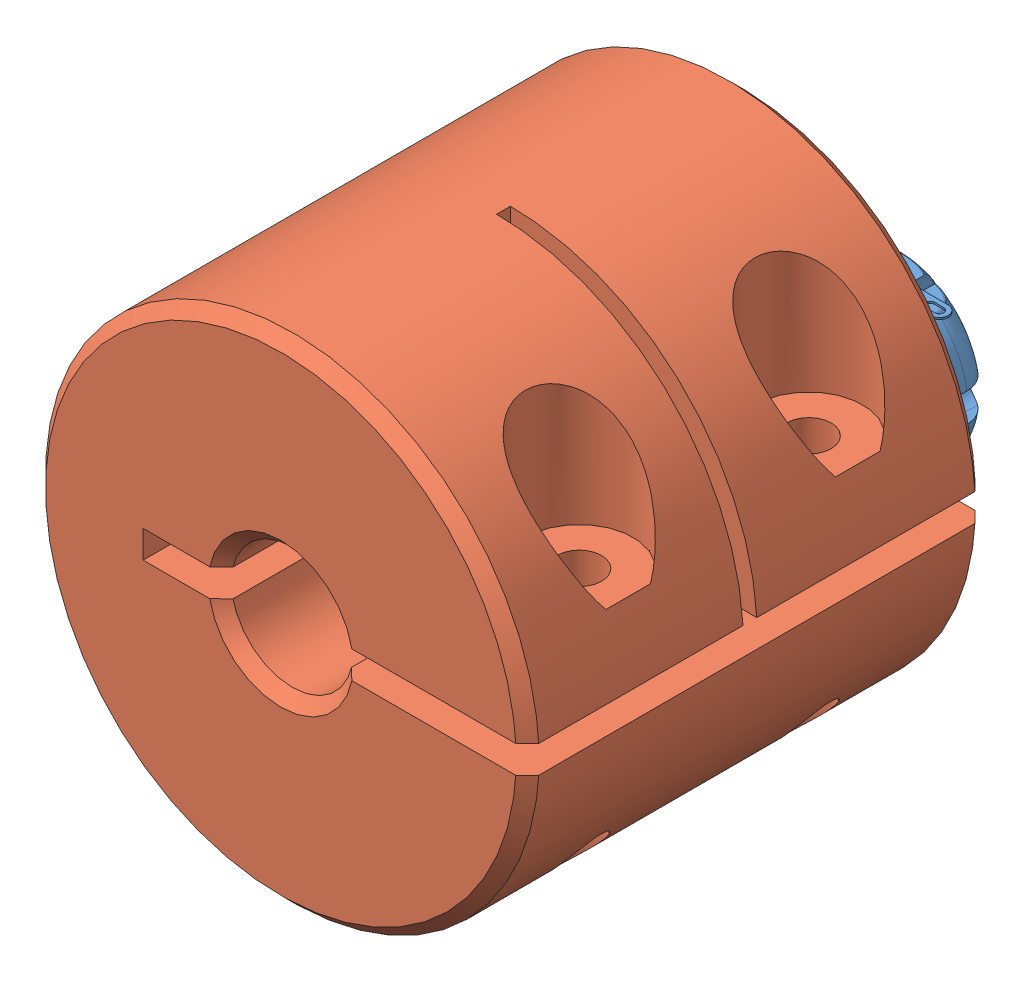
SolidWorks assembly Motor and Coupling, configuration Default. Lengths in mm.
Overall size (98.8 103.72 133.69).
2 component instances, 2 part files, 0 mates.
Components (placement in the parent):
- 3-6V_DC-Toy-Motor-1: 3-6V_DC-Toy-Motor [Default] at origin size (20 16.58 38)
- MS-P-SmallMotorCoupling-1: MS-P-SmallMotorCoupling [Default] at (61.539 68.9171 74.5924) size (54.57 54.61 50.8)
